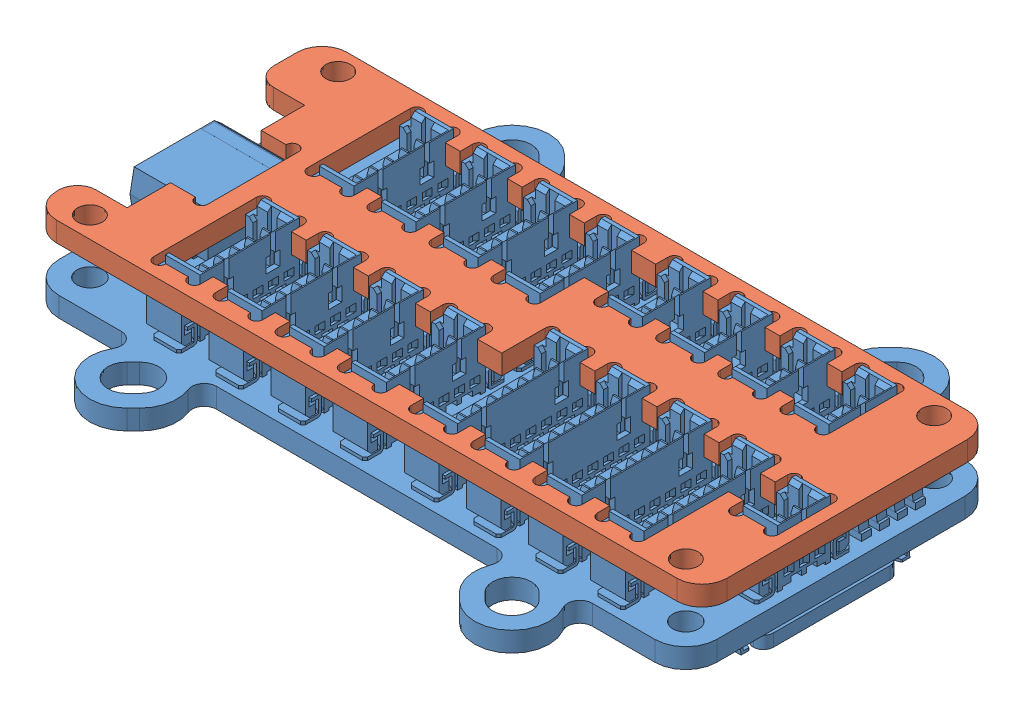
SolidWorks assembly test_ gabarit, configuration Défaut. Lengths in mm.
Overall size (54.55 9.16 37).
2 component instances, 2 part files, 3 mates.
Components (placement in the parent):
- Tawaki_v100-1: Tawaki_v100 [Défaut] at (-0.3802 1.6 55.875) x (1 0 0) z (0 -1 0) size (54.05 37 9.16)
- gabarit_soudage_molex_v0-1: gabarit_soudage_molex_v0 [Défaut] at (-124.3802 4.355 145.875) x (-1 0 0) z (0 0 -1) size (54 1.6 23.4)
Mates (geometry in assembly coordinates):
- Coïncidente4: coincident: plane of Tawaki_v100-1 through (25.4448 4.355 60.5) normal (0 1 0); plane of gabarit_soudage_molex_v0-1 through (24.6198 4.355 46.175) normal (0 -1 0)
- Coïncidente5: coincident: axis of Tawaki_v100-1 through (-24.3802 0 45.875) axis (0 1 0); axis of gabarit_soudage_molex_v0-1 through (-24.3802 5.955 45.875) axis (0 -1 0)
- Coïncidente6: coincident: axis of Tawaki_v100-1 through (23.6198 0 65.875) axis (0 1 0); axis of gabarit_soudage_molex_v0-1 through (23.6198 5.955 65.875) axis (0 -1 0)
